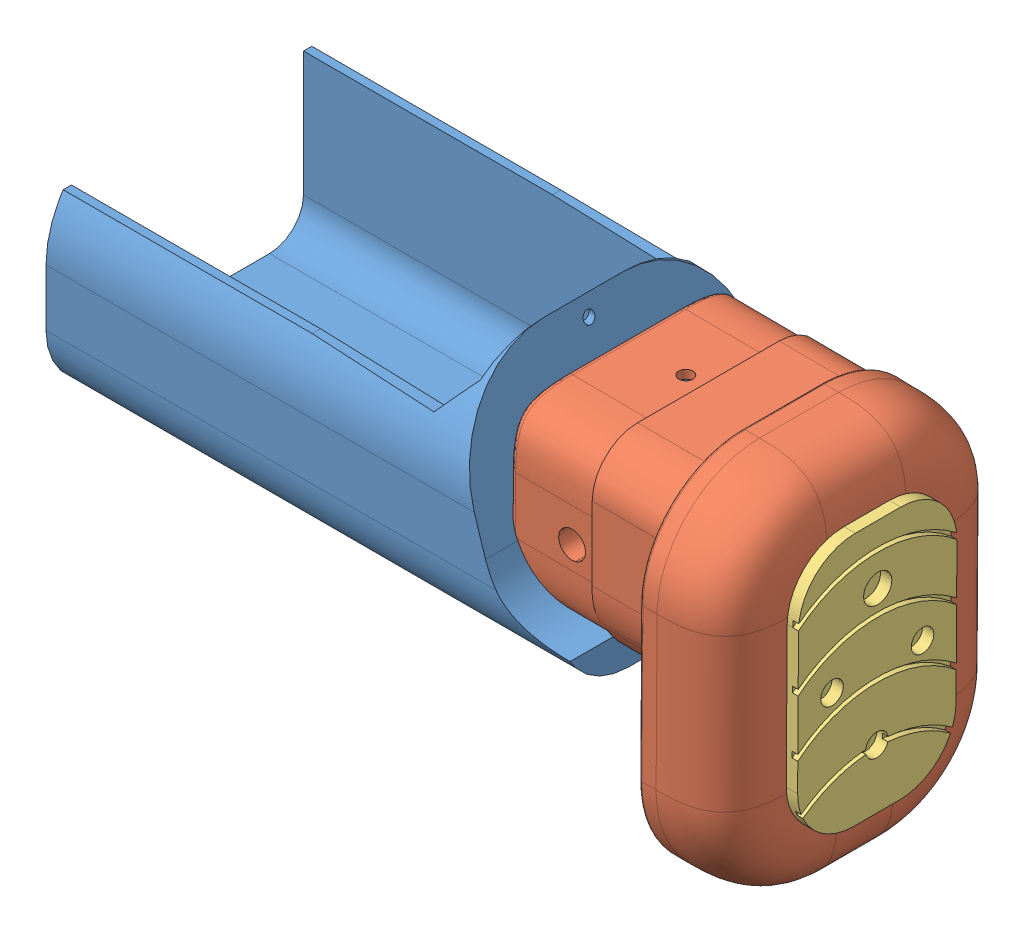
SolidWorks assembly Ensamblaje2, configuration Predeterminado. Lengths in mm.
Overall size (121.78 65.36 50.3).
3 component instances, 3 part files, 6 mates.
Components (placement in the parent):
- pinon Dispensador.STL-1: pinon Dispensador.STL [Predeterminado] at origin size (99.22 48 50)
- pie-1: pie [Predeterminado] at (35.2167 0.4343 -0.25) x (0.999982 -0.006065 0) z (0 0 1) size (43.1 65.1 50.1)
- print-1: print [Predeterminado] at (69.1463 -11.2717 -0.25) x (0 0 1) z (-0.999982 0.006065 0) size (28 45 5)
Mates (geometry in assembly coordinates):
- Coincidente3: coordinate: pinon Dispensador.STL-1
- Distancia1: distance: pinon Dispensador.STL-1, pie-1
- Concéntrica1: concentric: pinon Dispensador.STL-1, pie-1
- Concéntrica2: concentric: pie-1, print-1
- Coincidente4: coincident: pie-1, print-1
- Concéntrica3: concentric: pie-1, print-1
